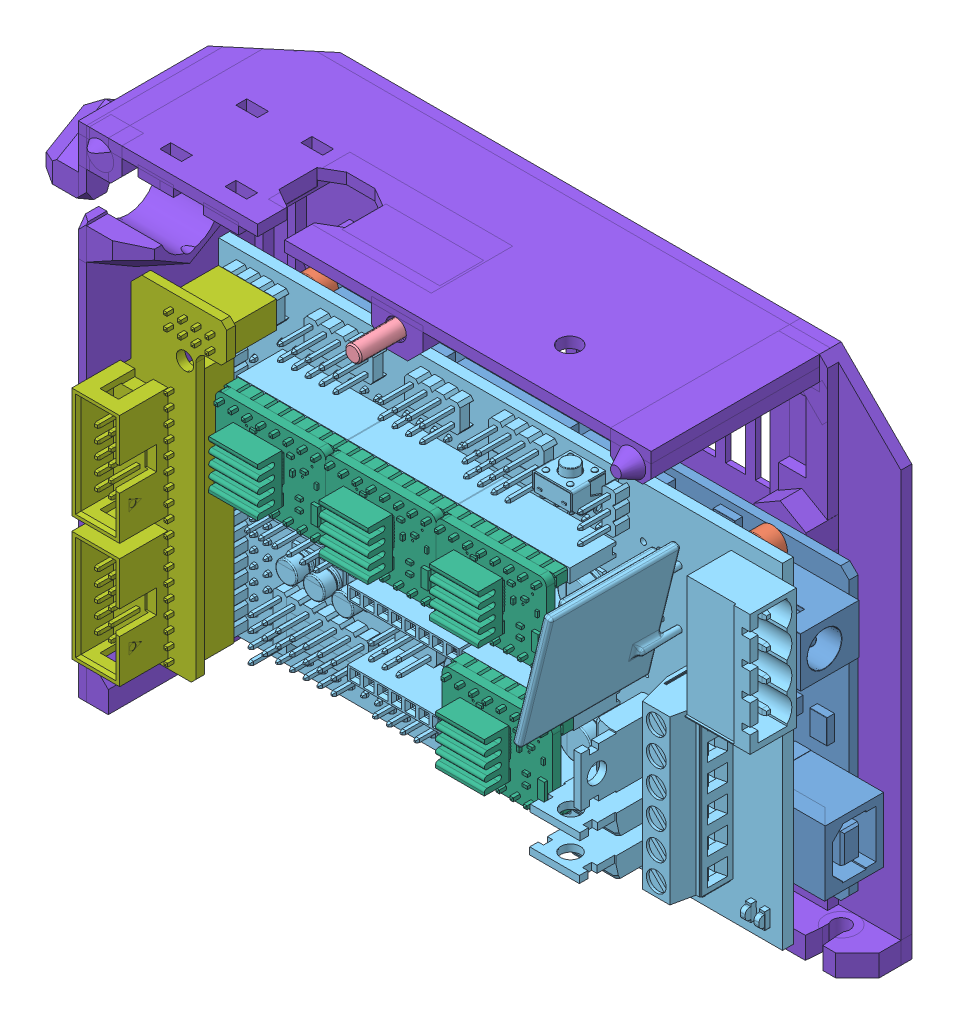
SolidWorks assembly Assembly ramps-base, configuration Valor predeterminado. Lengths in mm.
Overall size (130.96 92 50.19).
17 component instances, 8 part files, 48 mates.
Components (placement in the parent):
- Arduino Mega 2560-1: Arduino Mega 2560 [Valor predeterminado] at (57.1056 8.769 22.4871) x (1 0 0) z (0 0 -1) size (107.95 53.42 12.95)
- Screw DIN 912 - M3 x 10 --- 10N-1: Screw DIN 912 - M3 x 10 --- 10N [Valor predeterminado] at (18.65 -15.3991 25.4871) x (0 0 1) z (-0.998601 -0.052872 0) size (13 5.5 5.5)
- Nut DIN 934 - M3-1: Nut DIN 934 - M3 [Valor predeterminado] at (18.65 -15.3991 14.6361) x (0 0 1) z (-0.5 0.866025 0) size (2.4 5.5 6.35)
- Nut DIN 934 - M3-2: Nut DIN 934 - M3 [Valor predeterminado] at (93.7832 -15.3991 14.6361) x (0 0 1) z (0.5 0.866025 0) size (2.4 5.5 6.35)
- Nut DIN 934 - M3-3: Nut DIN 934 - M3 [Valor predeterminado] at (93.7832 32.9371 14.6361) x (0 0 1) z (0.5 0.866025 0) size (2.4 5.5 6.35)
- Nut DIN 934 - M3-4: Nut DIN 934 - M3 [Valor predeterminado] at (11.157 32.9371 14.6361) x (0 0 1) z (1 0 0) size (2.4 5.5 6.35)
- Screw DIN 912 - M3 x 10 --- 10N-2: Screw DIN 912 - M3 x 10 --- 10N [Valor predeterminado] at (93.7832 -15.3991 25.4871) x (0 0 1) z (-0.973921 -0.226886 0) size (13 5.5 5.5)
- Screw DIN 912 - M3 x 10 --- 10N-3: Screw DIN 912 - M3 x 10 --- 10N [Valor predeterminado] at (11.157 32.9371 25.4871) x (0 0 1) z (0.550712 0.834695 0) size (13 5.5 5.5)
- Screw DIN 912 - M3 x 10 --- 10N-4: Screw DIN 912 - M3 x 10 --- 10N [Valor predeterminado] at (93.7832 32.9371 25.4871) x (0 0 1) z (0.550712 0.834695 0) size (13 5.5 5.5)
- Screw DIN 912 - M3 x 40 --- 18N-1: Screw DIN 912 - M3 x 40 --- 18N [Valor predeterminado] at (49.8 57.6009 12.8361) x (0 0 -1) z (0.83561 0.549324 0) size (43 5.5 5.5)
- Shield Ramps 1.4-2: Shield Ramps 1.4 [Valor predeterminado] at (108.7635 12.736 33.6033) x (0 1 0) z (1 0 0) size (61.76 37.63 106.38)
- Driver A4988-1: Driver A4988 [Valor predeterminado] at (87.8289 82.4643 46.4093) x (-1 0 0) z (0 0 1) size (20.32 15.24 16.04)
- Driver A4988-2: Driver A4988 [Valor predeterminado] at (108.1489 82.4643 46.4093) x (-1 0 0) z (0 0 1) size (20.32 15.24 16.04)
- Driver A4988-3: Driver A4988 [Valor predeterminado] at (128.4689 82.4643 46.4093) x (-1 0 0) z (0 0 1) size (20.32 15.24 16.04)
- Driver A4988-4: Driver A4988 [Valor predeterminado] at (129.5994 59.472 46.4093) x (-1 0 0) z (0 0 1) size (20.32 15.24 16.04)
- Smart adapter conector LCD Ramps 1.4-1: Smart adapter conector LCD Ramps 1.4 [Valor predeterminado] at (11.3811 33.5685 46.6805) x (-1 0 0) z (0 1 0) size (20.12 19 60.45)
- RAMPS-cover-base-3: RAMPS-cover-base [Valor predeterminado] at (-8.7 -30.3991 12.8361) size (126.5 92 38)
Mates (geometry in assembly coordinates):
- Concêntrico2: concentric: cylinder of assembly; cylinder of assembly; cylinder of Arduino Mega 2560-1 through (18.65 -15.3991 20.8351) axis (0 0 1) radius 1.5621; cylinder of Screw DIN 912 - M3 x 10 --- 10N-1 through (18.65 -15.3991 25.4871) axis (0 0 1) radius 1.5
- Coincidente3: coincident: plane of assembly; plane of assembly; plane of Arduino Mega 2560-1 through (107.9056 35.4771 22.4871) normal (0 0 1); plane of Screw DIN 912 - M3 x 10 --- 10N-1 through (18.5046 -12.6529 22.4871) normal (0 0 -1)
- Concêntrico3: concentric: cylinder of assembly; cylinder of assembly; cylinder of Screw DIN 912 - M3 x 10 --- 10N-1 through (18.65 -15.3991 25.4871) axis (0 0 1) radius 1.5; cylinder of Nut DIN 934 - M3-1 through (18.65 -15.3991 15.8361) axis (0 0 -1) radius 1.25
- Concêntrico4: concentric: cylinder of assembly; cylinder of assembly; cylinder of Arduino Mega 2560-1 through (93.7832 -15.3991 20.8351) axis (0 0 1) radius 1.5621; cylinder of Screw DIN 912 - M3 x 10 --- 10N-2 through (93.7832 -15.3991 25.4871) axis (0 0 1) radius 1.5
- Coincidente7: coincident: plane of assembly; plane of assembly; plane of Arduino Mega 2560-1 through (107.9056 35.4771 22.4871) normal (0 0 1); plane of Screw DIN 912 - M3 x 10 --- 10N-2 through (93.1593 -12.7208 22.4871) normal (0 0 -1)
- Concêntrico5: concentric: cylinder of assembly; cylinder of assembly; cylinder of Arduino Mega 2560-1 through (93.7832 32.9371 20.8351) axis (0 0 1) radius 1.5621; cylinder of Screw DIN 912 - M3 x 10 --- 10N-4 through (93.7832 32.9371 25.4871) axis (0 0 1) radius 1.5
- Concêntrico6: concentric: cylinder of assembly; cylinder of assembly; cylinder of Arduino Mega 2560-1 through (11.157 32.9371 20.8351) axis (0 0 1) radius 1.5621; cylinder of Screw DIN 912 - M3 x 10 --- 10N-3 through (11.157 32.9371 25.4871) axis (0 0 1) radius 1.5
- Coincidente8: coincident: plane of assembly; plane of assembly; plane of Arduino Mega 2560-1 through (107.9056 35.4771 22.4871) normal (0 0 1); plane of Screw DIN 912 - M3 x 10 --- 10N-3 through (13.4524 31.4227 22.4871) normal (0 0 -1)
- Coincidente9: coincident: plane of assembly; plane of assembly; plane of Arduino Mega 2560-1 through (107.9056 35.4771 22.4871) normal (0 0 1); plane of Screw DIN 912 - M3 x 10 --- 10N-4 through (96.0786 31.4227 22.4871) normal (0 0 -1)
- Concêntrico7: concentric: cylinder of assembly; cylinder of assembly; cylinder of Nut DIN 934 - M3-3 through (93.7832 32.9371 15.8361) axis (0 0 -1) radius 1.25; cylinder of Screw DIN 912 - M3 x 10 --- 10N-4 through (93.7832 32.9371 25.4871) axis (0 0 1) radius 1.5
- Concêntrico8: concentric: cylinder of assembly; cylinder of assembly; cylinder of Nut DIN 934 - M3-2 through (93.7832 -15.3991 15.8361) axis (0 0 -1) radius 1.25; cylinder of Screw DIN 912 - M3 x 10 --- 10N-2 through (93.7832 -15.3991 25.4871) axis (0 0 1) radius 1.5
- Concêntrico9: concentric: cylinder of assembly; cylinder of assembly; cylinder of Nut DIN 934 - M3-4 through (11.157 32.9371 15.8361) axis (0 0 -1) radius 1.25; cylinder of Screw DIN 912 - M3 x 10 --- 10N-3 through (11.157 32.9371 25.4871) axis (0 0 1) radius 1.5
- Coincidente23: coincident: plane of assembly; plane of assembly; plane of Arduino Mega 2560-1 through (86.6458 -14.2053 31.0469) normal (0 0 1); plane of Shield Ramps 1.4-2 through (12.9096 -18.1777 31.0469) normal (0 0 -1)
- Paralelo8: parallel: plane of assembly; plane of assembly; plane of Arduino Mega 2560-1 through (65.894 -16.6691 31.0469) normal (0 -1 0); plane of Shield Ramps 1.4-2 through (108.7635 -18.1465 25.6033) normal (0 -1 0)
- Coincidente25: coincident: plane of assembly; plane of assembly; plane of Arduino Mega 2560-1 through (43.161 -16.6691 31.0469) normal (0 -1 0); plane of Shield Ramps 1.4-2 through (23.7996 -16.6691 31.0633) normal (0 -1 0)
- Coincidente26: coincident: plane of assembly; plane of assembly; plane of Arduino Mega 2560-1 through (10.3696 -16.7199 31.0469) normal (-1 0 0); plane of Shield Ramps 1.4-2 through (10.3696 -13.648 31.0469) normal (-1 0 0)
- Coincidente27: coincident: plane of assembly; plane of assembly; plane of Shield Ramps 1.4-2 through (16.7089 16.4243 44.1193) normal (0 -1 0); plane of Driver A4988-1 through (26.8689 16.4243 46.4093) normal (0 -1 0)
- Coincidente28: coincident: plane of assembly; plane of assembly; plane of Shield Ramps 1.4-2 through (16.7089 18.9243 44.1193) normal (0 0 1); plane of Driver A4988-1 through (33.2189 17.6693 44.1193) normal (0 0 -1)
- Coincidente29: coincident: plane of assembly; plane of assembly; plane of Shield Ramps 1.4-2 through (16.7089 31.2993 35.7693) normal (-1 0 0); plane of Driver A4988-1 through (16.7089 16.4243 46.4093) normal (-1 0 0)
- Coincidente30: coincident: plane of assembly; plane of assembly; plane of Shield Ramps 1.4-2 through (37.1189 16.4243 44.1193) normal (0 -1 0); plane of Driver A4988-2 through (44.6489 16.4243 46.4093) normal (0 -1 0)
- Coincidente31: coincident: plane of Shield Ramps 1.4-2 through (37.1189 18.9243 44.1193) normal (0 0 1); plane of Driver A4988-2 through (40.8389 17.6693 44.1193) normal (0 0 -1)
- Coincidente32: coincident: plane of Driver A4988-1 through (37.0289 18.9143 46.4093) normal (1 0 0); plane of Driver A4988-2 through (37.0289 16.4243 46.4093) normal (-1 0 0)
- Coincidente33: coincident: plane of assembly; plane of assembly; plane of Shield Ramps 1.4-2 through (57.5289 16.4243 44.1193) normal (0 -1 0); plane of Driver A4988-3 through (70.0489 16.4243 46.4093) normal (0 -1 0)
- Coincidente34: coincident: plane of Shield Ramps 1.4-2 through (57.5289 18.9243 44.1193) normal (0 0 1); plane of Driver A4988-3 through (61.1589 17.6693 44.1193) normal (0 0 -1)
- Coincidente35: coincident: plane of Driver A4988-2 through (57.3489 18.9143 46.4093) normal (1 0 0); plane of Driver A4988-3 through (57.3489 16.4243 46.4093) normal (-1 0 0)
- Coincidente36: coincident: plane of assembly; plane of assembly; plane of Shield Ramps 1.4-2 through (58.2294 -4.068 44.1193) normal (0 0 1); plane of Driver A4988-4 through (72.4494 -5.323 44.1193) normal (0 0 -1)
- Coincidente37: coincident: plane of Shield Ramps 1.4-2 through (58.2294 -6.568 44.1193) normal (0 -1 0); plane of Driver A4988-4 through (73.7194 -6.568 46.4093) normal (0 -1 0)
- Coincidente38: coincident: plane of Shield Ramps 1.4-2 through (78.7994 -4.543 35.7693) normal (1 0 0); plane of Driver A4988-4 through (78.7994 -4.078 46.4093) normal (1 0 0)
- Coincidente39: coincident: plane of assembly; plane of assembly; plane of Shield Ramps 1.4-2 through (10.3211 26.6169 38.1805) normal (0 0 1); plane of Smart adapter conector LCD Ramps 1.4-1 through (9.0511 6.1935 38.1805) normal (0 0 -1)
- Coincidente40: coincident: plane of Shield Ramps 1.4-2 through (10.3211 -9.5131 38.1805) normal (1 0 0); plane of Smart adapter conector LCD Ramps 1.4-1 through (10.3211 29.4185 38.1805) normal (1 0 0)
- Coincidente41: coincident: plane of Shield Ramps 1.4-2 through (17.3586 41.7585 38.1033) normal (0 1 0); plane of Smart adapter conector LCD Ramps 1.4-1 through (18.1211 41.7585 38.1805) normal (0 1 0)
- Coincidente42: coincident: plane of assembly; plane of assembly; plane of Arduino Mega 2560-1 through (107.9056 35.4771 20.8361) normal (0 0 -1); plane of RAMPS-cover-base-3 through (93.55 33.1009 20.8361) normal (0 0 1)
- Concêntrico11: concentric: cylinder of Screw DIN 912 - M3 x 10 --- 10N-1 through (18.65 -15.3991 25.4871) axis (0 0 1) radius 1.5; cylinder of RAMPS-cover-base-3 through (18.65 -15.3991 11.8361) axis (0 0 1) radius 1.9
- Paralelo9: parallel: plane of Arduino Mega 2560-1 through (6.3056 -17.9391 20.8361) normal (0 -1 0); plane of RAMPS-cover-base-3 through (-8.7 59.6009 12.8361) normal (0 -1 0)
- Paralelo10: parallel: line of Nut DIN 934 - M3-3; line of RAMPS-cover-base-3 through (95.15 35.8722 13.3361) axis (-1 0 0)
- Concêntrico12: concentric: cylinder of assembly; cylinder of assembly; cylinder of Nut DIN 934 - M3-3 through (93.7832 32.9371 15.8361) axis (0 0 -1) radius 1.25; cylinder of Screw DIN 912 - M3 x 10 --- 10N-4 through (93.7832 32.9371 25.4871) axis (0 0 1) radius 1.5
- Coincidente45: coincident: plane of Nut DIN 934 - M3-3 through (90.6078 32.9371 15.8361) normal (0 0 1); plane of RAMPS-cover-base-3 through (93.55 33.1009 15.8361) normal (0 0 -1)
- Paralelo11: parallel: plane of Nut DIN 934 - M3-2 through (95.3709 -18.1491 15.8361) normal (0.866025 -0.5 0); plane of RAMPS-cover-base-3
- Concêntrico13: concentric: cylinder of assembly; cylinder of assembly; cylinder of Nut DIN 934 - M3-2 through (93.7832 -15.3991 15.8361) axis (0 0 -1) radius 1.25; cylinder of Screw DIN 912 - M3 x 10 --- 10N-2 through (93.7832 -15.3991 25.4871) axis (0 0 1) radius 1.5
- Coincidente47: coincident: plane of Nut DIN 934 - M3-2 through (90.6078 -15.3991 15.8361) normal (0 0 1); plane of RAMPS-cover-base-3 through (93.55 -15.3991 15.8361) normal (0 0 -1)
- Concêntrico14: concentric: cylinder of Screw DIN 912 - M3 x 40 --- 18N-1 through (49.8 57.6009 12.8361) axis (0 0 -1) radius 1.5; cylinder of RAMPS-cover-base-3 through (49.8 57.6009 11.8361) axis (0 0 1) radius 1.9
- Coincidente48: coincident: plane of Screw DIN 912 - M3 x 40 --- 18N-1 through (48.2894 59.8988 15.8361) normal (0 0 1); plane of RAMPS-cover-base-3 through (49.8 57.6009 15.8361) normal (0 0 -1)
- Paralelo12: parallel: plane of Nut DIN 934 - M3-4 through (9.5693 35.6871 15.8361) normal (-0.866025 0.5 0); plane of RAMPS-cover-base-3
- Concêntrico15: concentric: cylinder of assembly; cylinder of assembly; cylinder of Nut DIN 934 - M3-4 through (11.157 32.9371 15.8361) axis (0 0 -1) radius 1.25; cylinder of Screw DIN 912 - M3 x 10 --- 10N-3 through (11.157 32.9371 25.4871) axis (0 0 1) radius 1.5
- Coincidente50: coincident: plane of Nut DIN 934 - M3-4 through (9.5693 35.6871 15.8361) normal (0 0 1); plane of RAMPS-cover-base-3 through (11 33.1009 15.8361) normal (0 0 -1)
- Paralelo13: parallel: plane of Nut DIN 934 - M3-1 through (17.0623 -12.6491 15.8361) normal (-0.866025 0.5 0); plane of RAMPS-cover-base-3
- Concêntrico16: concentric: cylinder of assembly; cylinder of assembly; cylinder of Screw DIN 912 - M3 x 10 --- 10N-1 through (18.65 -15.3991 25.4871) axis (0 0 1) radius 1.5; cylinder of Nut DIN 934 - M3-1 through (18.65 -15.3991 15.8361) axis (0 0 -1) radius 1.25
- Coincidente52: coincident: plane of Nut DIN 934 - M3-1 through (17.0623 -18.1491 15.8361) normal (0 0 1); plane of RAMPS-cover-base-3 through (18.65 -15.3991 15.8361) normal (0 0 -1)
